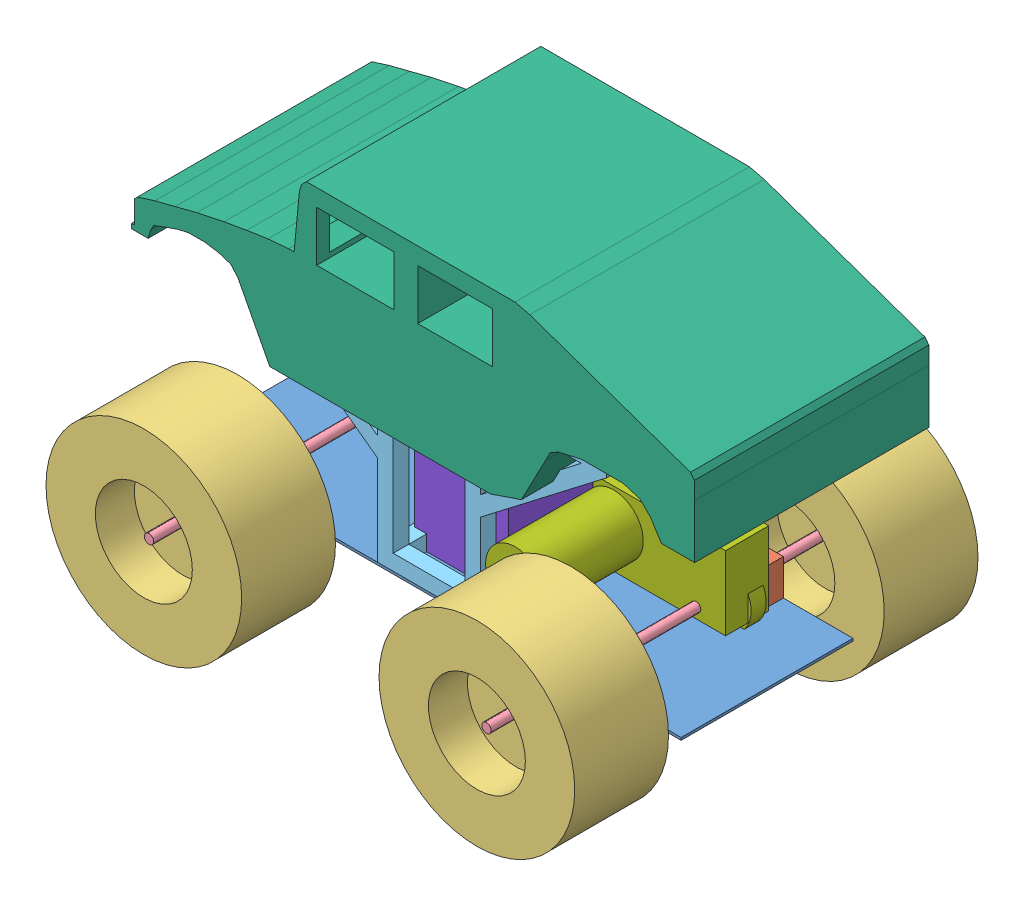
SolidWorks assembly сборка1, configuration Default. Lengths in mm.
Overall size (360.48 259.59 257.63).
15 component instances, 8 part files, 0 mates.
Components (placement in the parent):
- дно-1: дно [Default] at (-131.7868 1.3195 -26.6678) size (325 1.6 110)
- фланец-1: фланец [Default] at (-172.7077 14.432 77.297) x (1 0 0) z (0 0 -1) size (23 23 16)
- фланец-2: фланец [Default] at (39.8696 14.4098 77.3064) x (1 0 0) z (0 0 -1) size (23 23 16)
- фланец-3: фланец [Default] at (40.0467 14.4364 -22.6915) size (23 23 16)
- фланец-4: фланец [Default] at (-172.7102 14.4866 -22.7236) size (23 23 16)
- колесо-1: колесо [Default] at (-172.7559 14.4131 127.2093) size (125.21 125.21 60)
- колесо-2: колесо [Default] at (-172.6253 14.4857 -70.4246) size (125.21 125.21 60)
- колесо-3: колесо [Default] at (40.0167 14.4523 126.8822) size (125.21 125.21 60)
- колесо-4: колесо [Default] at (41.0518 15.2098 -70.1288) size (125.21 125.21 60)
- вал-1: вал [Default] at (-172.6383 14.4566 31.0421) size (6 6 246)
- вал-2: вал [Default] at (39.9813 14.4081 27.7298) size (6 6 246)
- рама2-1: рама2 [Default] at (-67.1138 2.9325 -27.6978) size (231 130 110)
- кузов1-1: кузов1 [Default] at (-48.5408 142.7517 -47.3856) size (360.25 114.2 150)
- MirrorMirrorредуктор-1: MirrorMirrorредуктор [Default] at (-3.6894 15.3116 16.5732) size (92.61 59.17 90.6)
- акб-1: акб [Default] at (-65.8979 3.0943 -6.1293) size (60 134 67)
